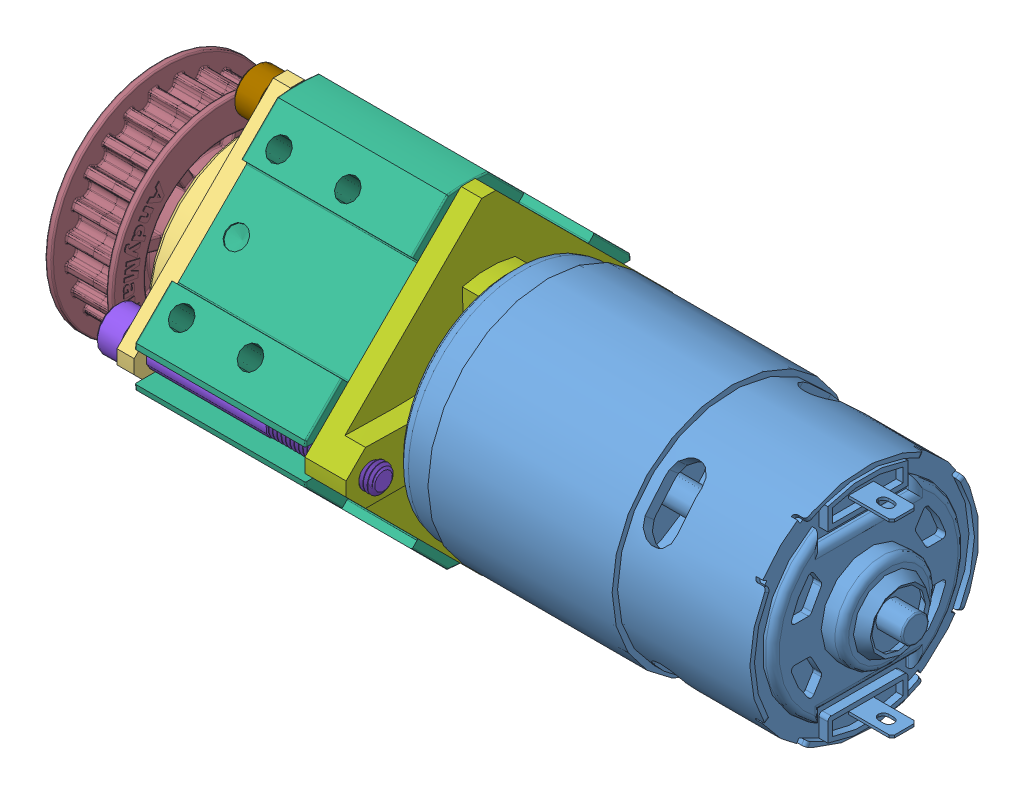
SolidWorks assembly 775Pro_Gearbox_Assem, configuration Default. Lengths in mm.
Overall size (149.24 67.43 67.43).
23 component instances, 13 part files, 9 mates.
Components (placement in the parent):
- am-3775+RedLine+Motor-1: am-3775+RedLine+Motor [Default] at origin size (87.75 44.3 43.54)
- am-3658+-+4_1+-+57+Sport-1: am-3658+-+4_1+-+57+Sport [Default] at (-23.368 0 0) x (0 0.707107 0.707107) z (-1 0 0) size (47.68 47.68 76.45)
  - am-XXXX - 57 Sport 500 Hex Output Plug-1: am-XXXX - 57 Sport 500 Hex Output Plug [Default] at (0 0 18.923) size (44.45 44.45 56.9)
    - am-XXXX - 57 Sport 500 Hex Shaft-1: am-XXXX - 57 Sport 500 Hex Shaft [Default] at (0 0 6.2738) x (0.999982 0.006056 0) z (0 0 1) size (16.1 12.67 56.9)
    - Output Block-1: Output Block [Default] at origin size (44.45 44.45 20.32)
    - FR8ZZ Bearing-1: FR8ZZ Bearing [Default] at (8.9053 -5.9773 -13.8938) x (0.999973 0.007281 0) z (0 0 1) size (31.75 31.75 7.95)
    - FR8ZZ Bearing-2: FR8ZZ Bearing [Default] at (5.8713 8.9755 6.2738) x (0.923728 0.383049 0) z (0 0 -1) size (31.75 31.75 7.95)
    - retaining Ring 0500 - Mcm 98410A122_98410A122-1: retaining Ring 0500 - Mcm 98410A122_98410A122 [Default] at (0 0 -14.3891) x (0 0 1) z (-0.999848 0.017452 0) size (0.89 16.1 14.34)
  - am-XXXX - 57 Sport 1 Stage Ring Gear Housing-1: am-XXXX - 57 Sport 1 Stage Ring Gear Housing [Default] at origin size (47.68 47.68 31.52)
  - am-3765 - 57 Sport Motor Block-1: am-3765 - 57 Sport Motor Block [Default] at (0 0 -19.558) x (0 1 0) z (0 0 1) size (45.76 47.07 8.89)
  - 10-32 x 1.750 SHCS_90128A953-1: 10-32 x 1.750 SHCS_90128A953 [Default] at (-17.9605 17.9605 -25.527) x (0.998431 -0.056 0) z (0 0 -1) size (7.92 7.92 49.5)
  - 10-32 x 1.750 SHCS_90128A953-2: 10-32 x 1.750 SHCS_90128A953 [Default] at (17.9605 -17.9605 -25.527) x (-0.998431 0.056 0) z (0 0 -1) size (7.92 7.92 49.5)
  - 10-32 X 375 SHCS_90128A940-1: 10-32 X 375 SHCS_90128A940 [Default] at (-17.9605 -17.9605 9.398) x (0.044358 0.999016 0) z (0 0 -1) size (7.92 7.92 14.58)
  - 10-32 X 375 SHCS_90128A940-2: 10-32 X 375 SHCS_90128A940 [Default] at (17.9605 17.9605 9.398) x (-0.044358 -0.999016 0) z (0 0 -1) size (7.92 7.92 14.58)
  - am-XXXX - 4_1 Input Stage-1: am-XXXX - 4_1 Input Stage [Default] at (0 0 1.5748) x (-0.494746 -0.869038 0) z (0 0 -1) size (35.15 35.15 14.63)
    - am-XXXX - 57 Sport Shaft Carrier Plate-1: am-XXXX - 57 Sport Shaft Carrier Plate [Default] at origin size (31.12 31.12 14.63)
    - 16T Planet Gear-1: 16T Planet Gear [Default] at (-11.8222 1.3023 11.8494) x (0 0 -1) z (1 0 0) size (7.09 12.42 12.42)
    - 16T Planet Gear-2: 16T Planet Gear [Default] at (1.3023 11.8222 11.8494) x (0 0 -1) z (0 -1 0) size (7.09 12.42 12.42)
    - 16T Planet Gear-3: 16T Planet Gear [Default] at (11.8222 -1.3023 11.8494) x (0 0 -1) z (-1 0 0) size (7.09 12.42 12.42)
    - 16T Planet Gear-4: 16T Planet Gear [Default] at (-1.3023 -11.8222 11.8494) x (0 0 -1) z (0 1 0) size (7.09 12.42 12.42)
  - Thrust washer - 775 Sport-1: Thrust washer - 775 Sport [Default] at (0 0 -14.478) x (0.890996 0.454011 0) z (0 0 1) size (31 31 1.52)
- am-3403+24+tooth+HTD+pulley+half+500hex-1: am-3403+24+tooth+HTD+pulley+half+500hex [Default] at (-58.4025 -25.8091 -14.6932) x (-1 0 0) z (0 -0.964341 0.264664) size (8.91 42 42)
- am-3403+24+tooth+HTD+pulley+half+500hex-2: am-3403+24+tooth+HTD+pulley+half+500hex [Default] at (-58.4025 -14.6932 25.8091) x (1 0 0) z (0 -0.964341 0.264664) size (8.91 42 42)
Mates (geometry in assembly coordinates):
- Concentric2: concentric aligned: cylinder of am-3775+RedLine+Motor-1 through (0 -14.5 0) axis (-1 0 0) radius 1.65; cylinder of am-3658+-+4_1+-+57+Sport-1/am-3765 - 57 Sport Motor Block-1 through (-8.89 -14.5 0) axis (-1 0 0) radius 2.25
- Coincident2: coincident anti-aligned: plane of am-3775+RedLine+Motor-1 through (0 8.9 0) normal (-1 0 0); plane of am-3658+-+4_1+-+57+Sport-1/am-3765 - 57 Sport Motor Block-1 through (0 0 0) normal (1 0 0)
- Concentric4: concentric aligned: cylinder of am-3775+RedLine+Motor-1 through (0 14.5 0) axis (-1 0 0) radius 1.65; cylinder of am-3658+-+4_1+-+57+Sport-1/am-3765 - 57 Sport Motor Block-1 through (-8.89 14.5 0) axis (-1 0 0) radius 2.25
- Concentric5: concentric anti-aligned: circle of am-3658+-+4_1+-+57+Sport-1/am-XXXX - 57 Sport 500 Hex Output Plug-1/am-XXXX - 57 Sport 500 Hex Shaft-1; circle of am-3403+24+tooth+HTD+pulley+half+500hex-1
- Parallel2: parallel: plane of am-3658+-+4_1+-+57+Sport-1/am-XXXX - 57 Sport 500 Hex Output Plug-1/am-XXXX - 57 Sport 500 Hex Shaft-1 through (-74.295 1.8511 -7.0797) normal (0 -0.264664 -0.964341); line of am-3403+24+tooth+HTD+pulley+half+500hex-1 through (-58.4025 1.8622 -7.1222) axis (0 -0.964341 0.264664)
- Concentric6: concentric aligned: cone of am-3403+24+tooth+HTD+pulley+half+500hex-1 through (-57.9388 4.8376 -8.4974) axis (1 0 0); cone of am-3403+24+tooth+HTD+pulley+half+500hex-2 through (-58.4025 4.8376 -8.4974) axis (1 0 0)
- Concentric7: concentric aligned: cone of am-3403+24+tooth+HTD+pulley+half+500hex-1 through (-57.9388 -4.8376 8.4974) axis (1 0 0); cone of am-3403+24+tooth+HTD+pulley+half+500hex-2 through (-58.4025 -4.8376 8.4974) axis (1 0 0)
- Coincident4: coincident anti-aligned: plane of am-3403+24+tooth+HTD+pulley+half+500hex-1 through (-58.4025 -4.847 -17.193) normal (-1 0 0); plane of am-3403+24+tooth+HTD+pulley+half+500hex-2 through (-58.4025 4.6083 17.2585) normal (1 0 0)
- Distance1: distance = 8.89 mm aligned: plane of am-3658+-+4_1+-+57+Sport-1/am-XXXX - 57 Sport 500 Hex Output Plug-1/am-XXXX - 57 Sport 500 Hex Shaft-1 through (-74.295 0 0) normal (-1 0 0); plane of am-3403+24+tooth+HTD+pulley+half+500hex-2 through (-65.405 0 0) normal (-1 0 0)
